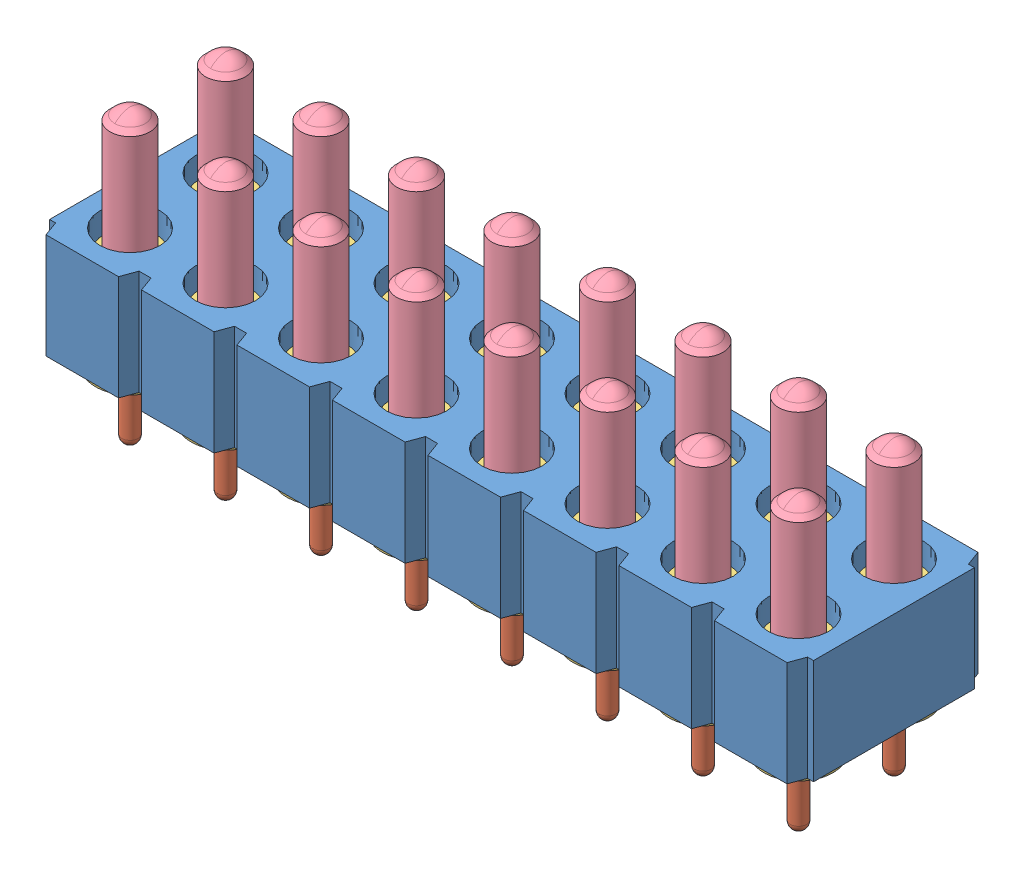
SolidWorks assembly mill-max-823-22-016-10-004101, configuration Default. Lengths in mm.
Overall size (20.32 7.75 5.08).
65 component instances, 5 part files, 0 mates.
Components (placement in the parent):
- mill-max-823-22-016-10-004101_P4XX-28-010-00-090000-1: mill-max-823-22-016-10-004101_P4XX-28-010-00-090000 [Default] at origin size (20.32 2.79 5.08)
- mill-max-823-22-016-10-004101_0963-0-1: mill-max-823-22-016-10-004101_0963-0 [Default] at (0.9644 -4.953 -1.27) x (0 1 0) z (0 0 1) size (4.04 1.31 1.31)
- mill-max-823-22-016-10-004101_0953-X-1: mill-max-823-22-016-10-004101_0953-X [Default] at (0.9644 -3.2004 -1.27) x (0 1 0) z (-0.980895 0 0.194537) size (2.69 1.83 1.83)
- mill-max-823-22-016-10-004101_0918-X-1: mill-max-823-22-016-10-004101_0918-X [Default] at (0.9644 -1.1938 -1.27) x (0 1 0) z (0 0 1) size (3.99 1.25 1.25)
- mill-max-823-22-016-10-004101_6875-0-00-00-75-XX-43-0C-1: mill-max-823-22-016-10-004101_6875-0-00-00-75-XX-43-0C [Default] at (0.9644 0.6557 -1.27) x (-0.956034 0 -0.293257) z (0 -1 0) size (0.2 0.07 3.45)
- mill-max-823-22-016-10-004101_0963-0-2: mill-max-823-22-016-10-004101_0963-0 [Default] at (0.9644 -4.953 -3.81) x (0 1 0) z (0 0 1) size (4.04 1.31 1.31)
- mill-max-823-22-016-10-004101_0953-X-2: mill-max-823-22-016-10-004101_0953-X [Default] at (0.9644 -3.2004 -3.81) x (0 1 0) z (0 0 1) size (2.69 1.83 1.83)
- mill-max-823-22-016-10-004101_0918-X-2: mill-max-823-22-016-10-004101_0918-X [Default] at (0.9644 -1.1938 -3.81) x (0 1 0) z (0.012366 0 0.999924) size (3.99 1.25 1.25)
- mill-max-823-22-016-10-004101_6875-0-00-00-75-XX-43-0C-2: mill-max-823-22-016-10-004101_6875-0-00-00-75-XX-43-0C [Default] at (0.9644 -2.5164 -3.81) x (-0.692815 0 0.721116) z (0 1 0) size (0.2 0.07 3.45)
- mill-max-823-22-016-10-004101_6875-0-00-00-75-XX-43-0C-3: mill-max-823-22-016-10-004101_6875-0-00-00-75-XX-43-0C [Default] at (3.5044 -2.5164 -3.81) x (-0.692815 0 0.721116) z (0 1 0) size (0.2 0.07 3.45)
- mill-max-823-22-016-10-004101_0918-X-3: mill-max-823-22-016-10-004101_0918-X [Default] at (3.5044 -1.1938 -3.81) x (0 1 0) z (0.012366 0 0.999924) size (3.99 1.25 1.25)
- mill-max-823-22-016-10-004101_0953-X-3: mill-max-823-22-016-10-004101_0953-X [Default] at (3.5044 -3.2004 -3.81) x (0 1 0) z (0 0 1) size (2.69 1.83 1.83)
- mill-max-823-22-016-10-004101_0963-0-3: mill-max-823-22-016-10-004101_0963-0 [Default] at (3.5044 -4.953 -3.81) x (0 1 0) z (0 0 1) size (4.04 1.31 1.31)
- mill-max-823-22-016-10-004101_6875-0-00-00-75-XX-43-0C-4: mill-max-823-22-016-10-004101_6875-0-00-00-75-XX-43-0C [Default] at (3.5044 0.6557 -1.27) x (-0.956034 0 -0.293257) z (0 -1 0) size (0.2 0.07 3.45)
- mill-max-823-22-016-10-004101_0918-X-4: mill-max-823-22-016-10-004101_0918-X [Default] at (3.5044 -1.1938 -1.27) x (0 1 0) z (0 0 1) size (3.99 1.25 1.25)
- mill-max-823-22-016-10-004101_0953-X-4: mill-max-823-22-016-10-004101_0953-X [Default] at (3.5044 -3.2004 -1.27) x (0 1 0) z (-0.980895 0 0.194537) size (2.69 1.83 1.83)
- mill-max-823-22-016-10-004101_0963-0-4: mill-max-823-22-016-10-004101_0963-0 [Default] at (3.5044 -4.953 -1.27) x (0 1 0) z (0 0 1) size (4.04 1.31 1.31)
- mill-max-823-22-016-10-004101_6875-0-00-00-75-XX-43-0C-5: mill-max-823-22-016-10-004101_6875-0-00-00-75-XX-43-0C [Default] at (6.0444 -2.5164 -3.81) x (-0.692815 0 0.721116) z (0 1 0) size (0.2 0.07 3.45)
- mill-max-823-22-016-10-004101_6875-0-00-00-75-XX-43-0C-6: mill-max-823-22-016-10-004101_6875-0-00-00-75-XX-43-0C [Default] at (8.5844 -2.5164 -3.81) x (-0.692815 0 0.721116) z (0 1 0) size (0.2 0.07 3.45)
- mill-max-823-22-016-10-004101_6875-0-00-00-75-XX-43-0C-7: mill-max-823-22-016-10-004101_6875-0-00-00-75-XX-43-0C [Default] at (11.1244 -2.5164 -3.81) x (-0.692815 0 0.721116) z (0 1 0) size (0.2 0.07 3.45)
- mill-max-823-22-016-10-004101_6875-0-00-00-75-XX-43-0C-8: mill-max-823-22-016-10-004101_6875-0-00-00-75-XX-43-0C [Default] at (13.6644 -2.5164 -3.81) x (-0.692815 0 0.721116) z (0 1 0) size (0.2 0.07 3.45)
- mill-max-823-22-016-10-004101_6875-0-00-00-75-XX-43-0C-9: mill-max-823-22-016-10-004101_6875-0-00-00-75-XX-43-0C [Default] at (16.2044 -2.5164 -3.81) x (-0.692815 0 0.721116) z (0 1 0) size (0.2 0.07 3.45)
- mill-max-823-22-016-10-004101_6875-0-00-00-75-XX-43-0C-10: mill-max-823-22-016-10-004101_6875-0-00-00-75-XX-43-0C [Default] at (18.7444 -2.5164 -3.81) x (-0.692815 0 0.721116) z (0 1 0) size (0.2 0.07 3.45)
- mill-max-823-22-016-10-004101_0918-X-5: mill-max-823-22-016-10-004101_0918-X [Default] at (6.0444 -1.1938 -3.81) x (0 1 0) z (0.012366 0 0.999924) size (3.99 1.25 1.25)
- mill-max-823-22-016-10-004101_0918-X-6: mill-max-823-22-016-10-004101_0918-X [Default] at (8.5844 -1.1938 -3.81) x (0 1 0) z (0.012366 0 0.999924) size (3.99 1.25 1.25)
- mill-max-823-22-016-10-004101_0918-X-7: mill-max-823-22-016-10-004101_0918-X [Default] at (11.1244 -1.1938 -3.81) x (0 1 0) z (0.012366 0 0.999924) size (3.99 1.25 1.25)
- mill-max-823-22-016-10-004101_0918-X-8: mill-max-823-22-016-10-004101_0918-X [Default] at (13.6644 -1.1938 -3.81) x (0 1 0) z (0.012366 0 0.999924) size (3.99 1.25 1.25)
- mill-max-823-22-016-10-004101_0918-X-9: mill-max-823-22-016-10-004101_0918-X [Default] at (16.2044 -1.1938 -3.81) x (0 1 0) z (0.012366 0 0.999924) size (3.99 1.25 1.25)
- mill-max-823-22-016-10-004101_0918-X-10: mill-max-823-22-016-10-004101_0918-X [Default] at (18.7444 -1.1938 -3.81) x (0 1 0) z (0.012366 0 0.999924) size (3.99 1.25 1.25)
- mill-max-823-22-016-10-004101_0953-X-5: mill-max-823-22-016-10-004101_0953-X [Default] at (6.0444 -3.2004 -3.81) x (0 1 0) z (0 0 1) size (2.69 1.83 1.83)
- mill-max-823-22-016-10-004101_0953-X-6: mill-max-823-22-016-10-004101_0953-X [Default] at (8.5844 -3.2004 -3.81) x (0 1 0) z (0 0 1) size (2.69 1.83 1.83)
- mill-max-823-22-016-10-004101_0953-X-7: mill-max-823-22-016-10-004101_0953-X [Default] at (11.1244 -3.2004 -3.81) x (0 1 0) z (0 0 1) size (2.69 1.83 1.83)
- mill-max-823-22-016-10-004101_0953-X-8: mill-max-823-22-016-10-004101_0953-X [Default] at (13.6644 -3.2004 -3.81) x (0 1 0) z (0 0 1) size (2.69 1.83 1.83)
- mill-max-823-22-016-10-004101_0953-X-9: mill-max-823-22-016-10-004101_0953-X [Default] at (16.2044 -3.2004 -3.81) x (0 1 0) z (0 0 1) size (2.69 1.83 1.83)
- mill-max-823-22-016-10-004101_0953-X-10: mill-max-823-22-016-10-004101_0953-X [Default] at (18.7444 -3.2004 -3.81) x (0 1 0) z (0 0 1) size (2.69 1.83 1.83)
- mill-max-823-22-016-10-004101_0963-0-5: mill-max-823-22-016-10-004101_0963-0 [Default] at (6.0444 -4.953 -3.81) x (0 1 0) z (0 0 1) size (4.04 1.31 1.31)
- mill-max-823-22-016-10-004101_0963-0-6: mill-max-823-22-016-10-004101_0963-0 [Default] at (8.5844 -4.953 -3.81) x (0 1 0) z (0 0 1) size (4.04 1.31 1.31)
- mill-max-823-22-016-10-004101_0963-0-7: mill-max-823-22-016-10-004101_0963-0 [Default] at (11.1244 -4.953 -3.81) x (0 1 0) z (0 0 1) size (4.04 1.31 1.31)
- mill-max-823-22-016-10-004101_0963-0-8: mill-max-823-22-016-10-004101_0963-0 [Default] at (13.6644 -4.953 -3.81) x (0 1 0) z (0 0 1) size (4.04 1.31 1.31)
- mill-max-823-22-016-10-004101_0963-0-9: mill-max-823-22-016-10-004101_0963-0 [Default] at (16.2044 -4.953 -3.81) x (0 1 0) z (0 0 1) size (4.04 1.31 1.31)
- mill-max-823-22-016-10-004101_0963-0-10: mill-max-823-22-016-10-004101_0963-0 [Default] at (18.7444 -4.953 -3.81) x (0 1 0) z (0 0 1) size (4.04 1.31 1.31)
- mill-max-823-22-016-10-004101_6875-0-00-00-75-XX-43-0C-11: mill-max-823-22-016-10-004101_6875-0-00-00-75-XX-43-0C [Default] at (6.0444 0.6557 -1.27) x (-0.956034 0 -0.293257) z (0 -1 0) size (0.2 0.07 3.45)
- mill-max-823-22-016-10-004101_6875-0-00-00-75-XX-43-0C-12: mill-max-823-22-016-10-004101_6875-0-00-00-75-XX-43-0C [Default] at (8.5844 0.6557 -1.27) x (-0.956034 0 -0.293257) z (0 -1 0) size (0.2 0.07 3.45)
- mill-max-823-22-016-10-004101_6875-0-00-00-75-XX-43-0C-13: mill-max-823-22-016-10-004101_6875-0-00-00-75-XX-43-0C [Default] at (11.1244 0.6557 -1.27) x (-0.956034 0 -0.293257) z (0 -1 0) size (0.2 0.07 3.45)
- mill-max-823-22-016-10-004101_6875-0-00-00-75-XX-43-0C-14: mill-max-823-22-016-10-004101_6875-0-00-00-75-XX-43-0C [Default] at (13.6644 0.6557 -1.27) x (-0.956034 0 -0.293257) z (0 -1 0) size (0.2 0.07 3.45)
- mill-max-823-22-016-10-004101_6875-0-00-00-75-XX-43-0C-15: mill-max-823-22-016-10-004101_6875-0-00-00-75-XX-43-0C [Default] at (16.2044 0.6557 -1.27) x (-0.956034 0 -0.293257) z (0 -1 0) size (0.2 0.07 3.45)
- mill-max-823-22-016-10-004101_6875-0-00-00-75-XX-43-0C-16: mill-max-823-22-016-10-004101_6875-0-00-00-75-XX-43-0C [Default] at (18.7444 0.6557 -1.27) x (-0.956034 0 -0.293257) z (0 -1 0) size (0.2 0.07 3.45)
- mill-max-823-22-016-10-004101_0918-X-11: mill-max-823-22-016-10-004101_0918-X [Default] at (6.0444 -1.1938 -1.27) x (0 1 0) z (0 0 1) size (3.99 1.25 1.25)
- mill-max-823-22-016-10-004101_0918-X-12: mill-max-823-22-016-10-004101_0918-X [Default] at (8.5844 -1.1938 -1.27) x (0 1 0) z (0 0 1) size (3.99 1.25 1.25)
- mill-max-823-22-016-10-004101_0918-X-13: mill-max-823-22-016-10-004101_0918-X [Default] at (11.1244 -1.1938 -1.27) x (0 1 0) z (0 0 1) size (3.99 1.25 1.25)
- mill-max-823-22-016-10-004101_0918-X-14: mill-max-823-22-016-10-004101_0918-X [Default] at (13.6644 -1.1938 -1.27) x (0 1 0) z (0 0 1) size (3.99 1.25 1.25)
- mill-max-823-22-016-10-004101_0918-X-15: mill-max-823-22-016-10-004101_0918-X [Default] at (16.2044 -1.1938 -1.27) x (0 1 0) z (0 0 1) size (3.99 1.25 1.25)
- mill-max-823-22-016-10-004101_0918-X-16: mill-max-823-22-016-10-004101_0918-X [Default] at (18.7444 -1.1938 -1.27) x (0 1 0) z (0 0 1) size (3.99 1.25 1.25)
- mill-max-823-22-016-10-004101_0953-X-11: mill-max-823-22-016-10-004101_0953-X [Default] at (6.0444 -3.2004 -1.27) x (0 1 0) z (-0.980895 0 0.194537) size (2.69 1.83 1.83)
- mill-max-823-22-016-10-004101_0953-X-12: mill-max-823-22-016-10-004101_0953-X [Default] at (8.5844 -3.2004 -1.27) x (0 1 0) z (-0.980895 0 0.194537) size (2.69 1.83 1.83)
- mill-max-823-22-016-10-004101_0953-X-13: mill-max-823-22-016-10-004101_0953-X [Default] at (11.1244 -3.2004 -1.27) x (0 1 0) z (-0.980895 0 0.194537) size (2.69 1.83 1.83)
- mill-max-823-22-016-10-004101_0953-X-14: mill-max-823-22-016-10-004101_0953-X [Default] at (13.6644 -3.2004 -1.27) x (0 1 0) z (-0.980895 0 0.194537) size (2.69 1.83 1.83)
- mill-max-823-22-016-10-004101_0953-X-15: mill-max-823-22-016-10-004101_0953-X [Default] at (16.2044 -3.2004 -1.27) x (0 1 0) z (-0.980895 0 0.194537) size (2.69 1.83 1.83)
- mill-max-823-22-016-10-004101_0953-X-16: mill-max-823-22-016-10-004101_0953-X [Default] at (18.7444 -3.2004 -1.27) x (0 1 0) z (-0.980895 0 0.194537) size (2.69 1.83 1.83)
- mill-max-823-22-016-10-004101_0963-0-11: mill-max-823-22-016-10-004101_0963-0 [Default] at (6.0444 -4.953 -1.27) x (0 1 0) z (0 0 1) size (4.04 1.31 1.31)
- mill-max-823-22-016-10-004101_0963-0-12: mill-max-823-22-016-10-004101_0963-0 [Default] at (8.5844 -4.953 -1.27) x (0 1 0) z (0 0 1) size (4.04 1.31 1.31)
- mill-max-823-22-016-10-004101_0963-0-13: mill-max-823-22-016-10-004101_0963-0 [Default] at (11.1244 -4.953 -1.27) x (0 1 0) z (0 0 1) size (4.04 1.31 1.31)
- mill-max-823-22-016-10-004101_0963-0-14: mill-max-823-22-016-10-004101_0963-0 [Default] at (13.6644 -4.953 -1.27) x (0 1 0) z (0 0 1) size (4.04 1.31 1.31)
- mill-max-823-22-016-10-004101_0963-0-15: mill-max-823-22-016-10-004101_0963-0 [Default] at (16.2044 -4.953 -1.27) x (0 1 0) z (0 0 1) size (4.04 1.31 1.31)
- mill-max-823-22-016-10-004101_0963-0-16: mill-max-823-22-016-10-004101_0963-0 [Default] at (18.7444 -4.953 -1.27) x (0 1 0) z (0 0 1) size (4.04 1.31 1.31)
